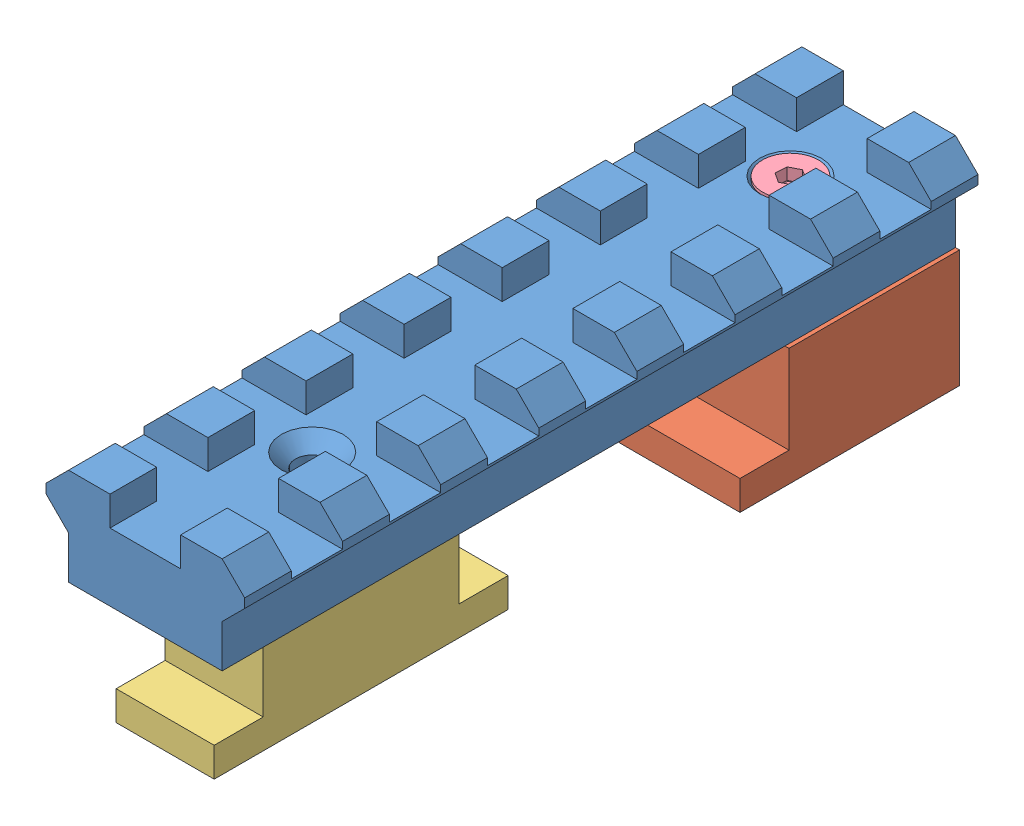
SolidWorks assembly Baugruppe1, configuration Standard. Lengths in mm.
Overall size (20.27 21.9 74.82).
5 component instances, 4 part files, 9 mates.
Components (placement in the parent):
- Rail-3: Rail [Standard] at (-4.1271 5.1584 0) size (20.27 9.9 74.82)
- flip_back-3: flip_back [Standard] at (-4.1271 -4.7457 0) x (0 0 1) z (-1 0 0) size (22.4 12 16.5)
- flip_front-1: flip_front [Standard] at (-4.1271 -4.7457 57.8) x (0 0 -1) z (1 0 0) size (30 12 10)
- Socket Countersunk Head Screw_DIN-2: Socket Countersunk Head Screw_DIN [DIN 7991 - M3 x 16 --- 12.8S] at (-4.1271 2.1584 57.8) x (0 -1 0) z (0 0 1) size (16 5.7 5.7) (hidden)
- Socket Countersunk Head Screw_DIN-3: Socket Countersunk Head Screw_DIN [DIN 7991 - M3 x 16 --- 12.8S] at (-4.1271 2.1584 9) x (0 -1 0) z (-0.546944 0 0.837169) size (16 5.7 5.7)
Mates (geometry in assembly coordinates):
- Deckungsgleich6: coincident: moEndPointRef_w of Rail-3; moEndPointRef_w of flip_back-3
- Deckungsgleich7: coincident: plane of Rail-3 through (-11.963 -4.7457 74.824) normal (0 -1 0); plane of flip_back-3 through (-12.3771 -4.7457 0) normal (0 1 0)
- Deckungsgleich8: coincident: line of Rail-3 through (-11.963 -4.7457 0) axis (1 0 0); line of flip_back-3 through (4.1229 -4.7457 0) axis (-1 0 0)
- Deckungsgleich11: coincident: plane of Rail-3 through (-11.963 -4.7457 74.824) normal (0 -1 0); plane of flip_front-1 through (0.8729 -4.7457 79.824) normal (0 1 0)
- Konzentrisch1: concentric: cone of Rail-3 through (-4.1271 2.1584 9) axis (0 -1 0); cone of Socket Countersunk Head Screw_DIN-3 through (-4.1271 1.8084 9) axis (0 -1 0)
- Deckungsgleich12: coincident: plane of Rail-3 through (-7.7316 2.1584 74.824) normal (0 1 0); plane of Socket Countersunk Head Screw_DIN-3 through (-4.1271 2.1584 9) normal (0 1 0)
- Konzentrisch3: concentric: cone of Rail-3 through (-4.1271 2.1612 57.8) axis (0 -1 0); cone of Socket Countersunk Head Screw_DIN-2 through (-4.1271 1.8084 57.8) axis (0 -1 0)
- Deckungsgleich13: coincident: plane of Rail-3 through (-7.7316 2.1584 74.824) normal (0 1 0); plane of Socket Countersunk Head Screw_DIN-2 through (-4.1271 2.1584 57.8) normal (0 1 0)
- Konzentrisch5: concentric: cylinder of Rail-3 through (-4.1271 5.1584 57.8) axis (0 1 0) radius 1.7; cylinder of flip_front-1 through (-4.1271 -4.7457 57.8) axis (0 1 0) radius 1.25
